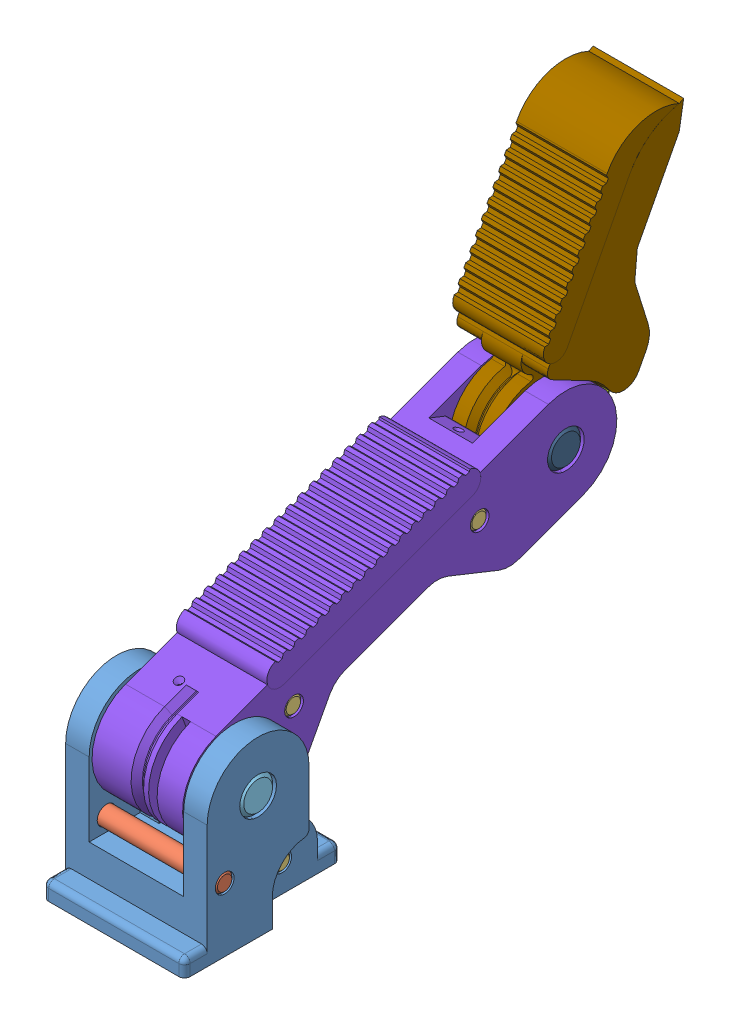
SolidWorks assembly block_finger_pp_t, configuration Default. Lengths in mm.
Overall size (25.4 90.81 104.27).
16 component instances, 10 part files, 30 mates.
Components (placement in the parent):
- c1_t-1: c1_t [Default] at origin size (25 30.67 32)
- 98381A475 D1-8 L1-1: 98381A475 D1-8 L1 [98381A475] at (-0.2 11.2575 -8.8732) size (25.4 3.17 3.17)
- 98381A472 D1-8 L5-8-3: 98381A472 D1-8 L5-8 [98381A472] at (0.0625 4.925 -23.535) size (15.88 3.17 3.17)
- 3434T31 - nylon pulley-1: 3434T31 - nylon pulley [Default] at (-0.15 4.925 -23.535) x (0 -1 0) z (0 0 1) size (9.5 2.4 9.5)
- 98381A472 D1-8 L5-8-1: 98381A472 D1-8 L5-8 [98381A472] at (0.0875 27.8748 -25.4819) size (15.88 3.17 3.17)
- 98381A472 D1-8 L5-8-2: 98381A472 D1-8 L5-8 [98381A472] at (0.0875 39.839 -58.2703) size (15.88 3.17 3.17)
- 98381A542 D1-4 L1-1: 98381A542 D1-4 L1 [98381A542] at (-0.2 21.67 -14.7858) size (25.4 6.35 6.35)
- 93365A120 4-40 insert-1: 93365A120 4-40 insert [93365A120] at (0 64.964 -86.0368) x (1 0 0) z (0 0.995964 -0.089757) size (4.37 3.82 4.37)
- 91253A106 4-40 L1-4 countersunk-1: 91253A106 4-40 L1-4 countersunk [91253A106] at (0 64.7736 -88.1494) x (1 0 0) z (0 -0.089757 -0.995964) size (6.48 6.48 6.63)
- finger_pp_t_A-1: finger_pp_t_A [Default] at (0.15 21.67 -14.7858) x (1 0 0) z (0 -0.342783 0.939415) size (16 20.25 80.5)
- finger_pp_t_B-1: finger_pp_t_B [Default] at (0 43.0939 -73.4992) x (1 0 0) z (0 -0.885802 0.464064) size (16 22.88 57.08)
- 98381A539 D1-4 L5-8-1: 98381A539 D1-4 L5-8 [98381A539] at (0.2125 43.0939 -73.4992) size (15.88 6.35 6.35)
- 93365A120 4-40 insert-2: 93365A120 4-40 insert [93365A120] at (0 43.6982 -83.9761) x (1 0 0) z (0 0.885802 -0.464064) size (4.37 3.82 4.37)
- 93365A120 4-40 insert-3: 93365A120 4-40 insert [93365A120] at (0.15 30.6972 -65.7809) x (-0.837169 0.187483 -0.513807) z (-0.546944 -0.286967 0.786449) size (4.37 3.82 4.37)
- 91253A106 4-40 L1-4 countersunk-2: 91253A106 4-40 L1-4 countersunk [91253A106] at (0 42.7139 -85.855) x (1 0 0) z (0 -0.464064 -0.885802) size (6.48 6.48 6.63)
- 91253A106 4-40 L1-4 countersunk-3: 91253A106 4-40 L1-4 countersunk [91253A106] at (0.15 28.7045 -66.5081) x (1 0 0) z (0 -0.939415 -0.342783) size (6.48 6.48 6.63)
Mates (geometry in assembly coordinates):
- Concentric1: concentric aligned: cylinder of c1_t-1 through (-12.5 21.67 -14.7858) axis (1 0 0) radius 3.25; cylinder of 98381A542 D1-4 L1-1 through (-12.9 21.67 -14.7858) axis (1 0 0) radius 3.175
- Coincident1: coincident aligned: plane of c1_t-1 through (12.5 21.67 -14.7858) normal (1 0 0); plane of 98381A542 D1-4 L1-1 through (12.5 21.67 -14.7858) normal (1 0 0)
- Concentric5: concentric aligned: cylinder of c1_t-1 through (-12.5 4.925 -23.535) axis (1 0 0) radius 1.6625; cylinder of 98381A472 D1-8 L5-8-3 through (-7.875 4.925 -23.535) axis (1 0 0) radius 1.5875
- Coincident5: coincident aligned: plane of c1_t-1 through (8 4.925 -23.535) normal (1 0 0); plane of 98381A472 D1-8 L5-8-3 through (8 4.925 -23.535) normal (1 0 0)
- Concentric6: concentric aligned: cylinder of c1_t-1 through (-12.5 11.2575 -8.8732) axis (1 0 0) radius 1.6625; cylinder of 98381A475 D1-8 L1-1 through (-12.9 11.2575 -8.8732) axis (1 0 0) radius 1.5875
- Coincident6: coincident aligned: plane of c1_t-1 through (12.5 21.67 -14.7858) normal (1 0 0); plane of 98381A475 D1-8 L1-1 through (12.5 11.2575 -8.8732) normal (1 0 0)
- Concentric8: concentric anti-aligned: circle of 93365A120 4-40 insert-1; circle of 91253A106 4-40 L1-4 countersunk-1
- Coincident8: coincident: circle of 93365A120 4-40 insert-1; cone of 91253A106 4-40 L1-4 countersunk-1 through (0 64.9628 -86.0497) axis (0 0.089757 0.995964)
- Concentric9: concentric aligned: cylinder of 98381A542 D1-4 L1-1 through (-12.9 21.67 -14.7858) axis (1 0 0) radius 3.175; cylinder of finger_pp_t_A-1 through (-7.85 21.67 -14.7858) axis (1 0 0) radius 3.525
- Distance2: distance = 0.2 mm anti-aligned: plane of finger_pp_t_A-1 through (8.15 21.67 -14.7858) normal (1 0 0); plane of c1_t-1 through (8.35 21.67 -14.7858) normal (-1 0 0)
- Concentric10: concentric aligned: cylinder of 98381A472 D1-8 L5-8-1 through (-7.85 27.8748 -25.4819) axis (1 0 0) radius 1.5875; cylinder of finger_pp_t_A-1 through (-7.85 27.8748 -25.4819) axis (1 0 0) radius 1.6625
- Coincident10: coincident aligned: plane of 98381A472 D1-8 L5-8-1 through (-7.85 27.8748 -25.4819) normal (-1 0 0); plane of finger_pp_t_A-1 through (-7.85 21.67 -14.7858) normal (-1 0 0)
- Concentric11: concentric aligned: cylinder of 98381A472 D1-8 L5-8-2 through (-7.85 39.839 -58.2703) axis (1 0 0) radius 1.5875; cylinder of finger_pp_t_A-1 through (-7.85 39.839 -58.2703) axis (1 0 0) radius 1.6625
- Coincident11: coincident aligned: plane of 98381A472 D1-8 L5-8-2 through (-7.85 39.839 -58.2703) normal (-1 0 0); plane of finger_pp_t_A-1 through (-7.85 21.67 -14.7858) normal (-1 0 0)
- Concentric12: concentric aligned: circle of 93365A120 4-40 insert-1; cylinder of finger_pp_t_B-1 through (0 65.3679 -81.5549) axis (0 -0.089757 -0.995964) radius 1.85
- Coincident12: coincident aligned: plane of 93365A120 4-40 insert-1 through (0 64.964 -86.0368) normal (0 -0.089757 -0.995964); plane of finger_pp_t_B-1 through (-13 67.4539 -86.2612) normal (0 -0.089757 -0.995964)
- Concentric13: concentric aligned: cylinder of finger_pp_t_A-1 through (-7.85 43.0939 -73.4992) axis (1 0 0) radius 3.25; cylinder of finger_pp_t_B-1 through (-8 43.0939 -73.4992) axis (1 0 0) radius 3.525
- Distance3: distance = 0.2 mm anti-aligned: plane of finger_pp_t_B-1 through (-3.5 43.0939 -73.4992) normal (-1 0 0); plane of finger_pp_t_A-1 through (-3.7 43.0939 -73.4992) normal (1 0 0)
- Concentric14: concentric aligned: cylinder of finger_pp_t_B-1 through (-8 43.0939 -73.4992) axis (1 0 0) radius 3.525; cylinder of 98381A539 D1-4 L5-8-1 through (-7.725 43.0939 -73.4992) axis (1 0 0) radius 3.175
- Coincident14: coincident aligned: plane of finger_pp_t_A-1 through (8.15 21.67 -14.7858) normal (1 0 0); plane of 98381A539 D1-4 L5-8-1 through (8.15 43.0939 -73.4992) normal (1 0 0)
- Concentric15: concentric anti-aligned: cylinder of 98381A472 D1-8 L5-8-3 through (-7.875 4.925 -23.535) axis (1 0 0) radius 1.5875; cylinder of 3434T31 - nylon pulley-1 through (-0.15 4.925 -23.535) axis (-1 0 0) radius 1.5
- Distance4: distance = 0.2 mm anti-aligned: plane of 3434T31 - nylon pulley-1 through (-1.35 3.425 -23.535) normal (-1 0 0); plane of c1_t-1 through (-1.55 4.925 -23.535) normal (1 0 0)
- Concentric16: concentric aligned: cylinder of finger_pp_t_A-1 through (0.15 34.9245 -64.2384) axis (0 -0.939415 -0.342783) radius 1.85; circle of 93365A120 4-40 insert-3
- Coincident16: coincident aligned: plane of finger_pp_t_A-1 through (8.15 13.2152 -17.8708) normal (0 -0.939415 -0.342783); plane of 93365A120 4-40 insert-3 through (0.15 30.6972 -65.7809) normal (0 -0.939415 -0.342783)
- Concentric17: concentric aligned: cylinder of finger_pp_t_B-1 through (0 45.5545 -80.4329) axis (0 -0.464064 -0.885802) radius 1.85; circle of 93365A120 4-40 insert-2
- Coincident17: coincident aligned: plane of finger_pp_t_B-1 through (8 38.9173 -81.4714) normal (0 -0.464064 -0.885802); plane of 93365A120 4-40 insert-2 through (0 43.6982 -83.9761) normal (0 -0.464064 -0.885802)
- Concentric18: concentric aligned: circle of finger_pp_t_B-1; circle of 91253A106 4-40 L1-4 countersunk-2
- Coincident18: coincident: circle of 93365A120 4-40 insert-2; cone of 91253A106 4-40 L1-4 countersunk-2 through (0 43.6922 -83.9876) axis (0 0.464064 0.885802)
- Concentric19: concentric anti-aligned: circle of 93365A120 4-40 insert-3; circle of 91253A106 4-40 L1-4 countersunk-3
- Coincident19: coincident: circle of 93365A120 4-40 insert-3; cone of 91253A106 4-40 L1-4 countersunk-3 through (0.15 30.685 -65.7854) axis (0 0.939415 0.342783)
